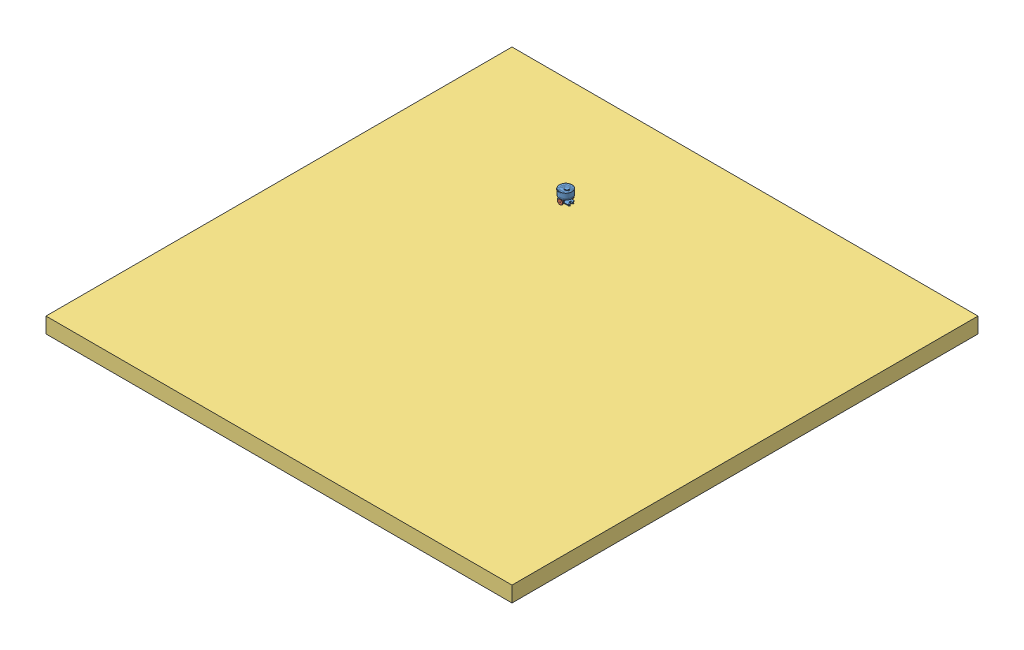
SolidWorks assembly _diff_bot, configuration Default. Lengths in mm.
Overall size (3000 179.93 3000).
4 component instances, 3 part files, 5 mates.
Components (placement in the parent):
- _bot-1: _bot [Default] at (-9.43 28.3554 -6.6495) x (1 0 0.000864) z (-0.000864 0 1) size (81.18 77.55 80.19)
- wheel-1: wheel [Default] at (-9.4012 38.6491 -39.9695) x (-1 0 -0.000864) z (0.000864 0 -1) size (32 32 8.6)
- wheel-2: wheel [Default] at (-9.4588 38.6491 26.6705) x (1 0 0.000864) z (-0.000864 0 1) size (32 32 8.6)
- ground-1: ground [Default] at (453.6901 -79.2242 802.4546) size (3000 100 3000)
Mates (geometry in assembly coordinates):
- Concentric1: concentric anti-aligned: cylinder of _bot-1 through (-9.4623 38.6491 30.7005) axis (0.000864 0 -1) radius 1.5; cylinder of wheel-2 through (-9.4542 38.6491 21.3705) axis (-0.000864 0 1) radius 1.5
- Coincident1: coincident aligned: plane of _bot-1 through (-9.4616 38.6491 29.9705) normal (-0.000864 0 1); plane of wheel-2 through (-9.4616 38.6491 29.9705) normal (-0.000864 0 1)
- Concentric2: concentric anti-aligned: cylinder of _bot-1 through (-9.3977 38.6491 -43.9995) axis (-0.000864 0 1) radius 1.5; cylinder of wheel-1 through (-9.4058 38.6491 -34.6695) axis (0.000864 0 -1) radius 1.5
- Coincident2: coincident aligned: plane of _bot-1 through (-9.3984 38.6491 -43.2695) normal (0.000864 0 -1); circle of wheel-1
- Parallel1: parallel anti-aligned: plane of _bot-1 through (-9.43 29.6491 -6.6495) normal (0 -1 0); plane of ground-1 through (453.6901 20.7758 802.4546) normal (0 1 0)
